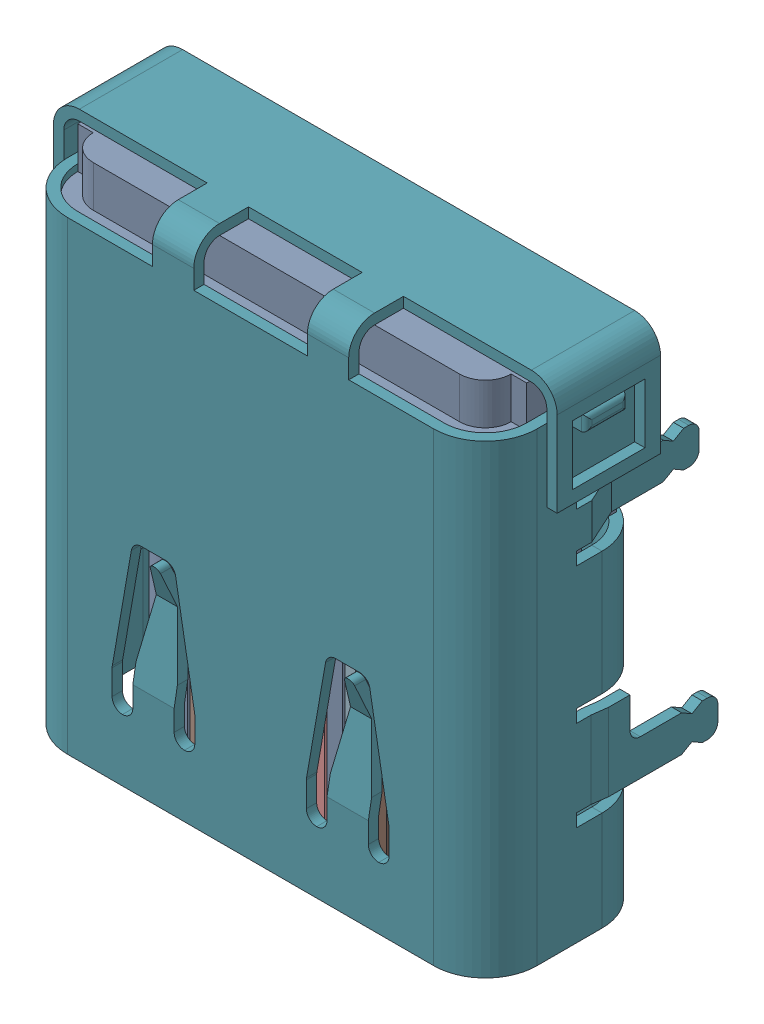
SolidWorks assembly USB1, configuration Défaut. Lengths in mm.
Overall size (9.75 9.87 4.46).
4 component instances, 1 part files, 0 mates.
Components (placement in the parent):
- KH-TYPE-C-24P-T9.87-1: KH-TYPE-C-24P-T9.87 [Défaut] at (59.3 -34.1968 -1.55) x (1 0 0) z (0 0 1) size (9.75 9.87 4.46)
  - 3D_PCB1_2021-12-30.step-1: 3D_PCB1_2021-12-30.step [Défaut] at origin size (9.75 9.87 4.46)
    - e9773ad0a1ba4615a8cdbe787346df90.step-1: e9773ad0a1ba4615a8cdbe787346df90.step [Défaut] at (5.0419 -6.8961 1.6) size (9.75 9.87 4.46)
      - COMPOUND.step_810-1: COMPOUND.step_810 [Défaut] at origin size (9.75 9.87 4.46)
